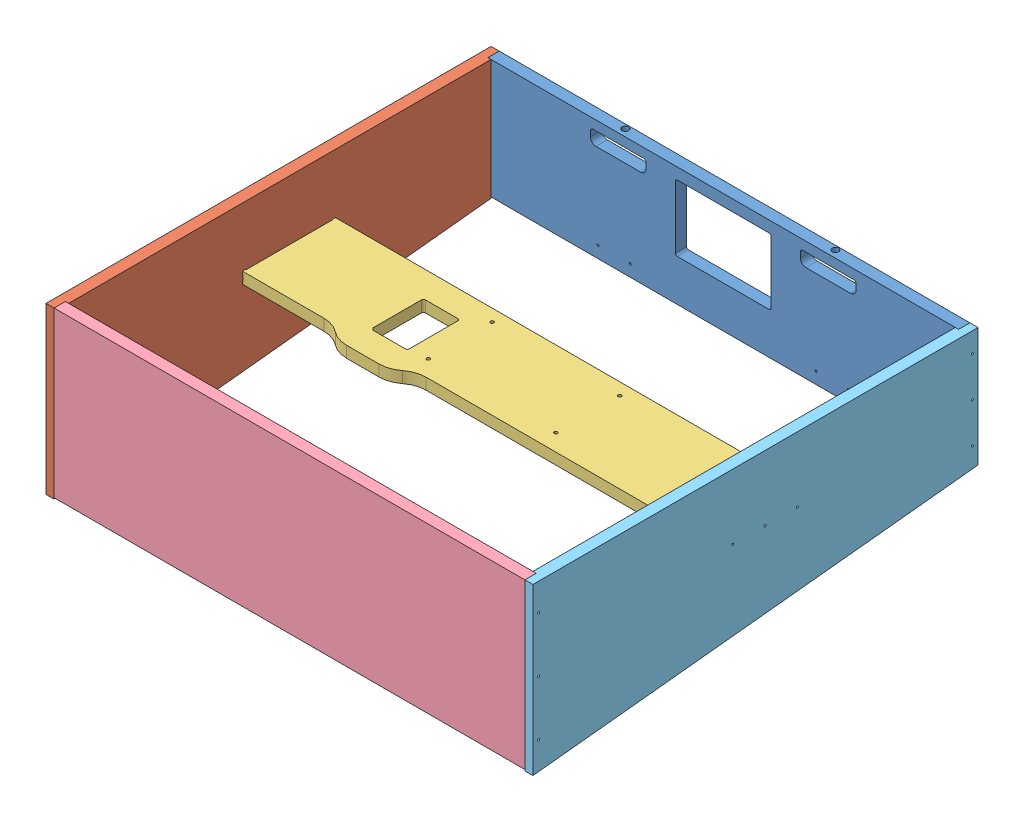
SolidWorks assembly 181226_GenericHead_1, configuration Default. Lengths in mm.
Overall size (765.81 260.35 700.09).
5 component instances, 5 part files, 12 mates.
Components (placement in the parent):
- 190302_GenericHead_2_Bottom-1: 190302_GenericHead_2_Bottom [Thickness_700] at origin size (740.41 187.33 17.78)
- 190302_GenericHead_2_LeftSide-1: 190302_GenericHead_2_LeftSide [Thickness_700] at (-598.17 0 839.47) x (0 0 -1) z (1 0 0) size (700.09 260.35 17.78)
- 181226_GenericHead_1_Brace-1: 181226_GenericHead_1_Brace [Thickness_700] at (-466.09 -5408.676 6257.6075) x (-1 0 0) z (0 1 0) size (740.41 165.1 17.78)
- 181226_GenericHead_1_Top-1: 181226_GenericHead_1_Top [Thickness_700] at (0 -11109.325 664.5275) x (1 0 0) z (0 0 -1) size (740.41 258.37 17.78)
- 190302_GenericHead_2_RightSide-1: 190302_GenericHead_2_RightSide [Thickness_700] at (132.08 -11328.4 839.47) x (0 0 -1) z (-1 0 0) size (700.09 260.35 17.78)
Mates (geometry in assembly coordinates):
- Coincident2: coincident aligned: plane of ?; plane of ?
- Coincident4: coincident anti-aligned: plane of ?; plane of ?
- Coincident5: coincident anti-aligned: plane of ?; plane of ?
- Coincident6: coincident anti-aligned: plane of ?; plane of ?
- Coincident9: coincident aligned: plane of ?; plane of ?
- Coincident11: coincident aligned: plane of ?; plane of ?
- Coincident13: coincident anti-aligned: plane of ?; plane of ?
- Coincident14: coincident anti-aligned: plane of ?; plane of ?
- Coincident15: coincident anti-aligned: plane of ?; plane of ?
- Coincident16: coincident anti-aligned: plane of ?; plane of ?
- Coincident17: coincident anti-aligned: plane of ?; plane of ?
- Coincident18: coincident anti-aligned: plane of ?; plane of ?
